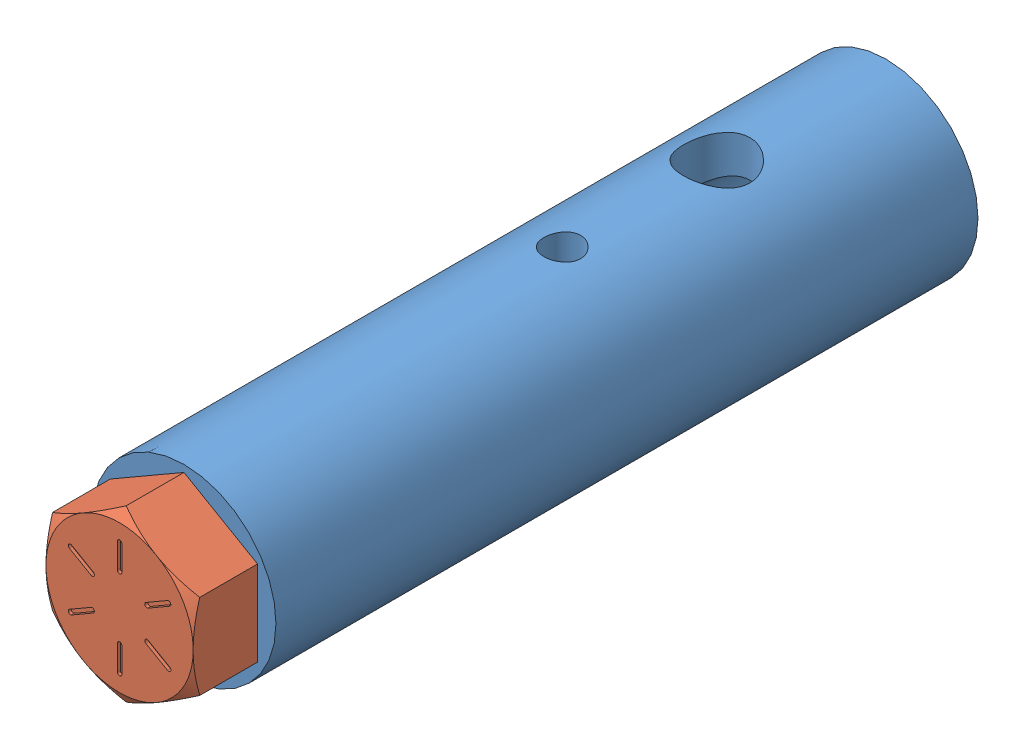
SolidWorks assembly Line Cutter Assembly, configuration Default. Lengths in mm.
Overall size (15.88 15.88 66.14).
3 component instances, 3 part files, 4 mates.
Components (placement in the parent):
- LINE CUTTER TUBE-1: LINE CUTTER TUBE [Default] at (22.1248 32.0677 16.1588) size (15.88 15.88 60.58)
- 92620A605_HIGH-STRENGTH GRADE 8 STEEL CAP SCREW-1: 92620A605_HIGH-STRENGTH GRADE 8 STEEL CAP SCREW [92620A605] at (22.1248 32.0677 73.1659) x (0 0 -1) z (1 0 0) size (18.63 14.66 12.7)
- Line Cutter Blade-1: Line Cutter Blade [Default] at (22.1248 32.0677 51.7188) x (0 -1 0) z (1 0 0) size (9.53 17.78 9.53)
Mates (geometry in assembly coordinates):
- Coincident1: coincident anti-aligned: plane of LINE CUTTER TUBE-1 through (22.1248 32.0677 76.7378) normal (0 0 1); plane of 92620A605_HIGH-STRENGTH GRADE 8 STEEL CAP SCREW-1 through (28.4748 35.7339 76.7378) normal (0 0 -1)
- Concentric1: concentric aligned: circle of LINE CUTTER TUBE-1; circle of 92620A605_HIGH-STRENGTH GRADE 8 STEEL CAP SCREW-1
- Concentric2: concentric anti-aligned: cylinder of LINE CUTTER TUBE-1 through (22.1248 32.0677 76.7378) axis (0 0 -1) radius 4.7625; cylinder of Line Cutter Blade-1 through (22.1248 32.0677 33.9388) axis (0 0 1) radius 4.7625
- Concentric7: concentric anti-aligned: cylinder of LINE CUTTER TUBE-1 through (22.1248 92.6467 44.0988) axis (0 -1 0) radius 1.5875; cylinder of Line Cutter Blade-1 through (22.1248 14.2877 44.0988) axis (0 1 0) radius 1.5875
